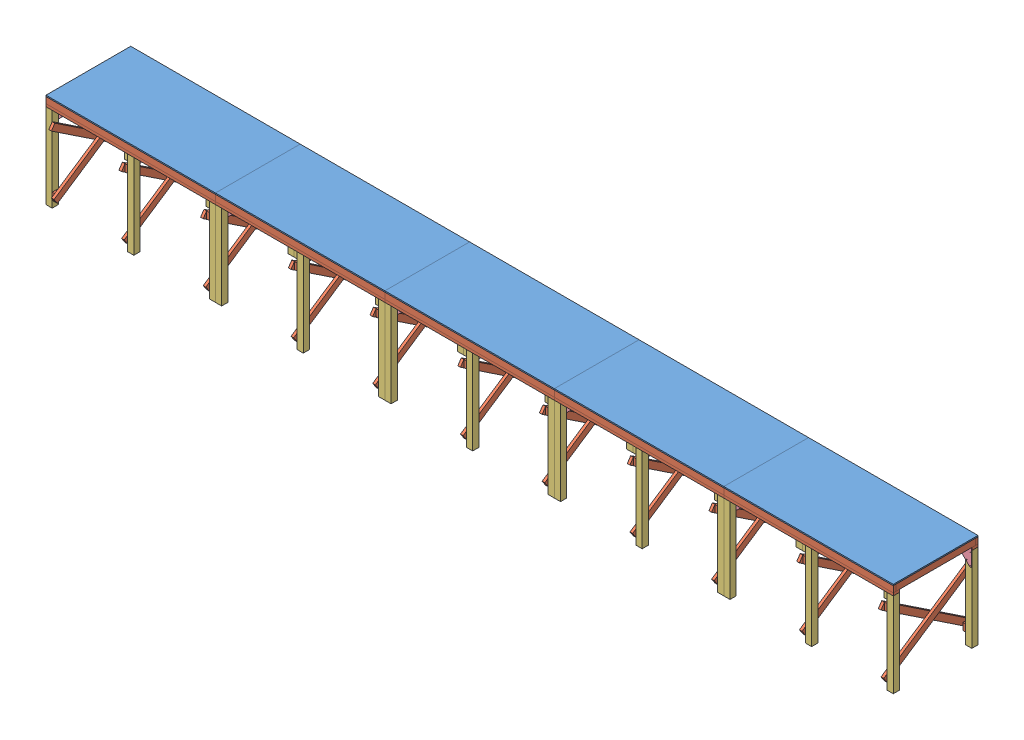
SolidWorks assembly Back Platform, configuration Default. Lengths in mm.
Overall size (12423.68 1373.14 1317.75).
179 component instances, 4 part files, 36 mates.
Components (placement in the parent):
- Platform Top-1: Platform Top [Default] at origin size (2438.4 106.76 1219.2)
  - 4x8-1: 4x8 [Default] at origin size (2438.4 17.86 1219.2)
  - 2x4 Configurable-6: 2x4 Configurable [96" Long] at (0 -53.3781 590.55) x (1 0 0) z (0 0 -1) size (2438.4 88.9 38.1)
  - 2x4 Configurable-7: 2x4 Configurable [96" Long] at (0 -53.3781 -590.55) x (1 0 0) z (0 0 -1) size (2438.4 88.9 38.1)
  - 2x4 Configurable-10: 2x4 Configurable [45" Long] at (-1200.15 -53.3781 0) x (0 0 -1) z (1 0 0) size (1143 88.9 38.1)
  - 2x4 Configurable-11: 2x4 Configurable [45" Long] at (-800.1 -53.3781 0) x (0 0 -1) z (1 0 0) size (1143 88.9 38.1)
  - 2x4 Configurable-12: 2x4 Configurable [45" Long] at (-400.05 -53.3781 0) x (0 0 -1) z (1 0 0) size (1143 88.9 38.1)
  - 2x4 Configurable-13: 2x4 Configurable [45" Long] at (0 -53.3781 0) x (0 0 -1) z (1 0 0) size (1143 88.9 38.1)
  - 2x4 Configurable-14: 2x4 Configurable [45" Long] at (400.05 -53.3781 0) x (0 0 -1) z (1 0 0) size (1143 88.9 38.1)
  - 2x4 Configurable-15: 2x4 Configurable [45" Long] at (800.1 -53.3781 0) x (0 0 -1) z (1 0 0) size (1143 88.9 38.1)
  - 2x4 Configurable-16: 2x4 Configurable [45" Long] at (1200.15 -53.3781 0) x (0 0 -1) z (1 0 0) size (1143 88.9 38.1)
- Stringer Config-1: Stringer Config [1 Wide 4ft High] at (-1510.4642 -1326.0215 -1043.4735) size (2670.08 1373.14 90.54)
  - 4x4 Configurable-1: 4x4 Configurable [48" Length] at (380.1642 -29.1066 522.7735) size (88.9 1219.2 88.9)
  - 2x4 Configurable-1: 2x4 Configurable [96" Long] at (1510.4642 1209.1434 478.3235) x (1 0 0) z (0 -1 0) size (2438.4 88.9 38.1)
  - 4x4 Configurable-2: 4x4 Configurable [48" Length] at (2729.6642 -29.1066 522.7735) size (88.9 1219.2 88.9)
  - Bracket-1: Bracket [Default] at (572.205 1228.1934 524.4153) x (0.707107 0.707107 0) z (0 0 -1) size (343.43 190.77 1.64)
  - Bracket-2: Bracket [Default] at (2448.7234 1228.1934 522.7735) x (-0.707107 0.707107 0) z (0 0 1) size (343.43 190.77 1.64)
  - 4x4 Configurable-4: 4x4 Configurable [48" Length] at (1466.0142 -29.1066 522.7735) x (0 0 1) z (-1 0 0) size (88.9 1219.2 88.9)
  - Bracket-3: Bracket [Default] at (1311.6697 1228.1934 524.4153) x (-1 0 0) z (0 0 -1) size (343.43 190.77 1.64)
- Stringer Config-2: Stringer Config [1 Wide 4ft High] at (1510.4642 -1326.0215 1043.4735) x (-1 0 0) z (0 0 -1) size (2670.08 1373.14 90.54)
  - 4x4 Configurable-1: 4x4 Configurable [48" Length] at (380.1642 -29.1066 522.7735) size (88.9 1219.2 88.9)
  - 2x4 Configurable-1: 2x4 Configurable [96" Long] at (1510.4642 1209.1434 478.3235) x (1 0 0) z (0 -1 0) size (2438.4 88.9 38.1)
  - 4x4 Configurable-2: 4x4 Configurable [48" Length] at (2729.6642 -29.1066 522.7735) size (88.9 1219.2 88.9)
  - Bracket-1: Bracket [Default] at (572.205 1228.1934 524.4153) x (0.707107 0.707107 0) z (0 0 -1) size (343.43 190.77 1.64)
  - Bracket-2: Bracket [Default] at (2448.7234 1228.1934 522.7735) x (-0.707107 0.707107 0) z (0 0 1) size (343.43 190.77 1.64)
  - 4x4 Configurable-4: 4x4 Configurable [48" Length] at (1466.0142 -29.1066 522.7735) x (0 0 1) z (-1 0 0) size (88.9 1219.2 88.9)
  - Bracket-3: Bracket [Default] at (1311.6697 1228.1934 524.4153) x (-1 0 0) z (0 0 -1) size (343.43 190.77 1.64)
- Stringer Config-3: Stringer Config [1 Wide 4ft High] at (927.9358 -1326.0215 -1043.4735) size (2670.08 1373.14 90.54)
  - 4x4 Configurable-1: 4x4 Configurable [48" Length] at (380.1642 -29.1066 522.7735) size (88.9 1219.2 88.9)
  - 2x4 Configurable-1: 2x4 Configurable [96" Long] at (1510.4642 1209.1434 478.3235) x (1 0 0) z (0 -1 0) size (2438.4 88.9 38.1)
  - 4x4 Configurable-2: 4x4 Configurable [48" Length] at (2729.6642 -29.1066 522.7735) size (88.9 1219.2 88.9)
  - Bracket-1: Bracket [Default] at (572.205 1228.1934 524.4153) x (0.707107 0.707107 0) z (0 0 -1) size (343.43 190.77 1.64)
  - Bracket-2: Bracket [Default] at (2448.7234 1228.1934 522.7735) x (-0.707107 0.707107 0) z (0 0 1) size (343.43 190.77 1.64)
  - 4x4 Configurable-4: 4x4 Configurable [48" Length] at (1466.0142 -29.1066 522.7735) x (0 0 1) z (-1 0 0) size (88.9 1219.2 88.9)
  - Bracket-3: Bracket [Default] at (1311.6697 1228.1934 524.4153) x (-1 0 0) z (0 0 -1) size (343.43 190.77 1.64)
- Platform Top-2: Platform Top [Default] at (2438.4 0 0) size (2438.4 106.76 1219.2)
  - 4x8-1: 4x8 [Default] at origin size (2438.4 17.86 1219.2)
  - 2x4 Configurable-6: 2x4 Configurable [96" Long] at (0 -53.3781 590.55) x (1 0 0) z (0 0 -1) size (2438.4 88.9 38.1)
  - 2x4 Configurable-7: 2x4 Configurable [96" Long] at (0 -53.3781 -590.55) x (1 0 0) z (0 0 -1) size (2438.4 88.9 38.1)
  - 2x4 Configurable-10: 2x4 Configurable [45" Long] at (-1200.15 -53.3781 0) x (0 0 -1) z (1 0 0) size (1143 88.9 38.1)
  - 2x4 Configurable-11: 2x4 Configurable [45" Long] at (-800.1 -53.3781 0) x (0 0 -1) z (1 0 0) size (1143 88.9 38.1)
  - 2x4 Configurable-12: 2x4 Configurable [45" Long] at (-400.05 -53.3781 0) x (0 0 -1) z (1 0 0) size (1143 88.9 38.1)
  - 2x4 Configurable-13: 2x4 Configurable [45" Long] at (0 -53.3781 0) x (0 0 -1) z (1 0 0) size (1143 88.9 38.1)
  - 2x4 Configurable-14: 2x4 Configurable [45" Long] at (400.05 -53.3781 0) x (0 0 -1) z (1 0 0) size (1143 88.9 38.1)
  - 2x4 Configurable-15: 2x4 Configurable [45" Long] at (800.1 -53.3781 0) x (0 0 -1) z (1 0 0) size (1143 88.9 38.1)
  - 2x4 Configurable-16: 2x4 Configurable [45" Long] at (1200.15 -53.3781 0) x (0 0 -1) z (1 0 0) size (1143 88.9 38.1)
- Stringer Config-4: Stringer Config [1 Wide 4ft High] at (3948.8642 -1326.0215 1043.4735) x (-1 0 0) z (0 0 -1) size (2670.08 1373.14 90.54)
  - 4x4 Configurable-1: 4x4 Configurable [48" Length] at (380.1642 -29.1066 522.7735) size (88.9 1219.2 88.9)
  - 2x4 Configurable-1: 2x4 Configurable [96" Long] at (1510.4642 1209.1434 478.3235) x (1 0 0) z (0 -1 0) size (2438.4 88.9 38.1)
  - 4x4 Configurable-2: 4x4 Configurable [48" Length] at (2729.6642 -29.1066 522.7735) size (88.9 1219.2 88.9)
  - Bracket-1: Bracket [Default] at (572.205 1228.1934 524.4153) x (0.707107 0.707107 0) z (0 0 -1) size (343.43 190.77 1.64)
  - Bracket-2: Bracket [Default] at (2448.7234 1228.1934 522.7735) x (-0.707107 0.707107 0) z (0 0 1) size (343.43 190.77 1.64)
  - 4x4 Configurable-4: 4x4 Configurable [48" Length] at (1466.0142 -29.1066 522.7735) x (0 0 1) z (-1 0 0) size (88.9 1219.2 88.9)
  - Bracket-3: Bracket [Default] at (1311.6697 1228.1934 524.4153) x (-1 0 0) z (0 0 -1) size (343.43 190.77 1.64)
- Stringer Config-7: Stringer Config [1 Wide 4ft High] at (-927.9358 -1326.0215 1043.4735) x (-1 0 0) z (0 0 -1) size (2670.08 1373.14 90.54)
  - 4x4 Configurable-1: 4x4 Configurable [48" Length] at (380.1642 -29.1066 522.7735) size (88.9 1219.2 88.9)
  - 2x4 Configurable-1: 2x4 Configurable [96" Long] at (1510.4642 1209.1434 478.3235) x (1 0 0) z (0 -1 0) size (2438.4 88.9 38.1)
  - 4x4 Configurable-2: 4x4 Configurable [48" Length] at (2729.6642 -29.1066 522.7735) size (88.9 1219.2 88.9)
  - Bracket-1: Bracket [Default] at (572.205 1228.1934 524.4153) x (0.707107 0.707107 0) z (0 0 -1) size (343.43 190.77 1.64)
  - Bracket-2: Bracket [Default] at (2448.7234 1228.1934 522.7735) x (-0.707107 0.707107 0) z (0 0 1) size (343.43 190.77 1.64)
  - 4x4 Configurable-4: 4x4 Configurable [48" Length] at (1466.0142 -29.1066 522.7735) x (0 0 1) z (-1 0 0) size (88.9 1219.2 88.9)
  - Bracket-3: Bracket [Default] at (1311.6697 1228.1934 524.4153) x (-1 0 0) z (0 0 -1) size (343.43 190.77 1.64)
- Platform Top-4: Platform Top [Default] at (-2438.4 0 0) size (2438.4 106.76 1219.2)
  - 4x8-1: 4x8 [Default] at origin size (2438.4 17.86 1219.2)
  - 2x4 Configurable-6: 2x4 Configurable [96" Long] at (0 -53.3781 590.55) x (1 0 0) z (0 0 -1) size (2438.4 88.9 38.1)
  - 2x4 Configurable-7: 2x4 Configurable [96" Long] at (0 -53.3781 -590.55) x (1 0 0) z (0 0 -1) size (2438.4 88.9 38.1)
  - 2x4 Configurable-10: 2x4 Configurable [45" Long] at (-1200.15 -53.3781 0) x (0 0 -1) z (1 0 0) size (1143 88.9 38.1)
  - 2x4 Configurable-11: 2x4 Configurable [45" Long] at (-800.1 -53.3781 0) x (0 0 -1) z (1 0 0) size (1143 88.9 38.1)
  - 2x4 Configurable-12: 2x4 Configurable [45" Long] at (-400.05 -53.3781 0) x (0 0 -1) z (1 0 0) size (1143 88.9 38.1)
  - 2x4 Configurable-13: 2x4 Configurable [45" Long] at (0 -53.3781 0) x (0 0 -1) z (1 0 0) size (1143 88.9 38.1)
  - 2x4 Configurable-14: 2x4 Configurable [45" Long] at (400.05 -53.3781 0) x (0 0 -1) z (1 0 0) size (1143 88.9 38.1)
  - 2x4 Configurable-15: 2x4 Configurable [45" Long] at (800.1 -53.3781 0) x (0 0 -1) z (1 0 0) size (1143 88.9 38.1)
  - 2x4 Configurable-16: 2x4 Configurable [45" Long] at (1200.15 -53.3781 0) x (0 0 -1) z (1 0 0) size (1143 88.9 38.1)
- Stringer Config-8: Stringer Config [1 Wide 4ft High] at (-3948.8642 -1326.0215 -1043.4735) size (2670.08 1373.14 90.54)
  - 4x4 Configurable-1: 4x4 Configurable [48" Length] at (380.1642 -29.1066 522.7735) size (88.9 1219.2 88.9)
  - 2x4 Configurable-1: 2x4 Configurable [96" Long] at (1510.4642 1209.1434 478.3235) x (1 0 0) z (0 -1 0) size (2438.4 88.9 38.1)
  - 4x4 Configurable-2: 4x4 Configurable [48" Length] at (2729.6642 -29.1066 522.7735) size (88.9 1219.2 88.9)
  - Bracket-1: Bracket [Default] at (572.205 1228.1934 524.4153) x (0.707107 0.707107 0) z (0 0 -1) size (343.43 190.77 1.64)
  - Bracket-2: Bracket [Default] at (2448.7234 1228.1934 522.7735) x (-0.707107 0.707107 0) z (0 0 1) size (343.43 190.77 1.64)
  - 4x4 Configurable-4: 4x4 Configurable [48" Length] at (1466.0142 -29.1066 522.7735) x (0 0 1) z (-1 0 0) size (88.9 1219.2 88.9)
  - Bracket-3: Bracket [Default] at (1311.6697 1228.1934 524.4153) x (-1 0 0) z (0 0 -1) size (343.43 190.77 1.64)
- Platform Top-5: Platform Top [Default] at (-4876.8 0 0) size (2438.4 106.76 1219.2)
  - 4x8-1: 4x8 [Default] at origin size (2438.4 17.86 1219.2)
  - 2x4 Configurable-6: 2x4 Configurable [96" Long] at (0 -53.3781 590.55) x (1 0 0) z (0 0 -1) size (2438.4 88.9 38.1)
  - 2x4 Configurable-7: 2x4 Configurable [96" Long] at (0 -53.3781 -590.55) x (1 0 0) z (0 0 -1) size (2438.4 88.9 38.1)
  - 2x4 Configurable-10: 2x4 Configurable [45" Long] at (-1200.15 -53.3781 0) x (0 0 -1) z (1 0 0) size (1143 88.9 38.1)
  - 2x4 Configurable-11: 2x4 Configurable [45" Long] at (-800.1 -53.3781 0) x (0 0 -1) z (1 0 0) size (1143 88.9 38.1)
  - 2x4 Configurable-12: 2x4 Configurable [45" Long] at (-400.05 -53.3781 0) x (0 0 -1) z (1 0 0) size (1143 88.9 38.1)
  - 2x4 Configurable-13: 2x4 Configurable [45" Long] at (0 -53.3781 0) x (0 0 -1) z (1 0 0) size (1143 88.9 38.1)
  - 2x4 Configurable-14: 2x4 Configurable [45" Long] at (400.05 -53.3781 0) x (0 0 -1) z (1 0 0) size (1143 88.9 38.1)
  - 2x4 Configurable-15: 2x4 Configurable [45" Long] at (800.1 -53.3781 0) x (0 0 -1) z (1 0 0) size (1143 88.9 38.1)
  - 2x4 Configurable-16: 2x4 Configurable [45" Long] at (1200.15 -53.3781 0) x (0 0 -1) z (1 0 0) size (1143 88.9 38.1)
- Stringer Config-9: Stringer Config [1 Wide 4ft High] at (-6387.2642 -1326.0215 -1043.4735) size (2670.08 1373.14 90.54)
  - 4x4 Configurable-1: 4x4 Configurable [48" Length] at (380.1642 -29.1066 522.7735) size (88.9 1219.2 88.9)
  - 2x4 Configurable-1: 2x4 Configurable [96" Long] at (1510.4642 1209.1434 478.3235) x (1 0 0) z (0 -1 0) size (2438.4 88.9 38.1)
  - 4x4 Configurable-2: 4x4 Configurable [48" Length] at (2729.6642 -29.1066 522.7735) size (88.9 1219.2 88.9)
  - Bracket-1: Bracket [Default] at (572.205 1228.1934 524.4153) x (0.707107 0.707107 0) z (0 0 -1) size (343.43 190.77 1.64)
  - Bracket-2: Bracket [Default] at (2448.7234 1228.1934 522.7735) x (-0.707107 0.707107 0) z (0 0 1) size (343.43 190.77 1.64)
  - 4x4 Configurable-4: 4x4 Configurable [48" Length] at (1466.0142 -29.1066 522.7735) x (0 0 1) z (-1 0 0) size (88.9 1219.2 88.9)
  - Bracket-3: Bracket [Default] at (1311.6697 1228.1934 524.4153) x (-1 0 0) z (0 0 -1) size (343.43 190.77 1.64)
- Stringer Config-10: Stringer Config [1 Wide 4ft High] at (-3366.3358 -1326.0215 1043.4735) x (-1 0 0) z (0 0 -1) size (2670.08 1373.14 90.54)
  - 4x4 Configurable-1: 4x4 Configurable [48" Length] at (380.1642 -29.1066 522.7735) size (88.9 1219.2 88.9)
  - 2x4 Configurable-1: 2x4 Configurable [96" Long] at (1510.4642 1209.1434 478.3235) x (1 0 0) z (0 -1 0) size (2438.4 88.9 38.1)
  - 4x4 Configurable-2: 4x4 Configurable [48" Length] at (2729.6642 -29.1066 522.7735) size (88.9 1219.2 88.9)
  - Bracket-1: Bracket [Default] at (572.205 1228.1934 524.4153) x (0.707107 0.707107 0) z (0 0 -1) size (343.43 190.77 1.64)
  - Bracket-2: Bracket [Default] at (2448.7234 1228.1934 522.7735) x (-0.707107 0.707107 0) z (0 0 1) size (343.43 190.77 1.64)
  - 4x4 Configurable-4: 4x4 Configurable [48" Length] at (1466.0142 -29.1066 522.7735) x (0 0 1) z (-1 0 0) size (88.9 1219.2 88.9)
  - Bracket-3: Bracket [Default] at (1311.6697 1228.1934 524.4153) x (-1 0 0) z (0 0 -1) size (343.43 190.77 1.64)
- Stringer Config-11: Stringer Config [1 Wide 4ft High] at (6387.2642 -1326.0215 1043.4735) x (-1 0 0) z (0 0 -1) size (2670.08 1373.14 90.54)
  - 4x4 Configurable-1: 4x4 Configurable [48" Length] at (380.1642 -29.1066 522.7735) size (88.9 1219.2 88.9)
  - 2x4 Configurable-1: 2x4 Configurable [96" Long] at (1510.4642 1209.1434 478.3235) x (1 0 0) z (0 -1 0) size (2438.4 88.9 38.1)
  - 4x4 Configurable-2: 4x4 Configurable [48" Length] at (2729.6642 -29.1066 522.7735) size (88.9 1219.2 88.9)
  - Bracket-1: Bracket [Default] at (572.205 1228.1934 524.4153) x (0.707107 0.707107 0) z (0 0 -1) size (343.43 190.77 1.64)
  - Bracket-2: Bracket [Default] at (2448.7234 1228.1934 522.7735) x (-0.707107 0.707107 0) z (0 0 1) size (343.43 190.77 1.64)
  - 4x4 Configurable-4: 4x4 Configurable [48" Length] at (1466.0142 -29.1066 522.7735) x (0 0 1) z (-1 0 0) size (88.9 1219.2 88.9)
  - Bracket-3: Bracket [Default] at (1311.6697 1228.1934 524.4153) x (-1 0 0) z (0 0 -1) size (343.43 190.77 1.64)
- Platform Top-6: Platform Top [Default] at (4876.8 0 0) size (2438.4 106.76 1219.2)
  - 4x8-1: 4x8 [Default] at origin size (2438.4 17.86 1219.2)
  - 2x4 Configurable-6: 2x4 Configurable [96" Long] at (0 -53.3781 590.55) x (1 0 0) z (0 0 -1) size (2438.4 88.9 38.1)
  - 2x4 Configurable-7: 2x4 Configurable [96" Long] at (0 -53.3781 -590.55) x (1 0 0) z (0 0 -1) size (2438.4 88.9 38.1)
  - 2x4 Configurable-10: 2x4 Configurable [45" Long] at (-1200.15 -53.3781 0) x (0 0 -1) z (1 0 0) size (1143 88.9 38.1)
  - 2x4 Configurable-11: 2x4 Configurable [45" Long] at (-800.1 -53.3781 0) x (0 0 -1) z (1 0 0) size (1143 88.9 38.1)
  - 2x4 Configurable-12: 2x4 Configurable [45" Long] at (-400.05 -53.3781 0) x (0 0 -1) z (1 0 0) size (1143 88.9 38.1)
  - 2x4 Configurable-13: 2x4 Configurable [45" Long] at (0 -53.3781 0) x (0 0 -1) z (1 0 0) size (1143 88.9 38.1)
  - 2x4 Configurable-14: 2x4 Configurable [45" Long] at (400.05 -53.3781 0) x (0 0 -1) z (1 0 0) size (1143 88.9 38.1)
  - 2x4 Configurable-15: 2x4 Configurable [45" Long] at (800.1 -53.3781 0) x (0 0 -1) z (1 0 0) size (1143 88.9 38.1)
  - 2x4 Configurable-16: 2x4 Configurable [45" Long] at (1200.15 -53.3781 0) x (0 0 -1) z (1 0 0) size (1143 88.9 38.1)
- Stringer Config-12: Stringer Config [1 Wide 4ft High] at (3366.3358 -1326.0215 -1043.4735) size (2670.08 1373.14 90.54)
  - 4x4 Configurable-1: 4x4 Configurable [48" Length] at (380.1642 -29.1066 522.7735) size (88.9 1219.2 88.9)
  - 2x4 Configurable-1: 2x4 Configurable [96" Long] at (1510.4642 1209.1434 478.3235) x (1 0 0) z (0 -1 0) size (2438.4 88.9 38.1)
  - 4x4 Configurable-2: 4x4 Configurable [48" Length] at (2729.6642 -29.1066 522.7735) size (88.9 1219.2 88.9)
  - Bracket-1: Bracket [Default] at (572.205 1228.1934 524.4153) x (0.707107 0.707107 0) z (0 0 -1) size (343.43 190.77 1.64)
  - Bracket-2: Bracket [Default] at (2448.7234 1228.1934 522.7735) x (-0.707107 0.707107 0) z (0 0 1) size (343.43 190.77 1.64)
  - 4x4 Configurable-4: 4x4 Configurable [48" Length] at (1466.0142 -29.1066 522.7735) x (0 0 1) z (-1 0 0) size (88.9 1219.2 88.9)
  - Bracket-3: Bracket [Default] at (1311.6697 1228.1934 524.4153) x (-1 0 0) z (0 0 -1) size (343.43 190.77 1.64)
- 2x4 Configurable-1: 2x4 Configurable [60" Long] at (-4978.4 -736.2604 0) x (0 0.554276 0.832333) z (-1 0 0) size (1524 88.9 38.1)
- 2x4 Configurable-2: 2x4 Configurable [60" Long] at (-4940.3 -798.4838 0) x (0 -0.554276 0.832333) z (-1 0 0) size (1524 88.9 38.1)
- 2x4 Configurable-7: 2x4 Configurable [4" Long] at (-4940.3 -327.7047 565.15) x (0 -1 0) z (1 0 0) size (101.6 88.9 38.1)
- 2x4 Configurable-25: 2x4 Configurable [4" Long] at (-4940.3 -1144.8161 -565.15) x (0 -1 0) z (1 0 0) size (101.6 88.9 38.1)
- 2x4 Configurable-26: 2x4 Configurable [4" Long] at (-2501.9 -327.7047 565.15) x (0 -1 0) z (1 0 0) size (101.6 88.9 38.1)
- 2x4 Configurable-27: 2x4 Configurable [4" Long] at (-63.5 -327.7047 565.15) x (0 -1 0) z (1 0 0) size (101.6 88.9 38.1)
- 2x4 Configurable-28: 2x4 Configurable [4" Long] at (2374.9 -327.7047 565.15) x (0 -1 0) z (1 0 0) size (101.6 88.9 38.1)
- 2x4 Configurable-29: 2x4 Configurable [4" Long] at (4813.3 -327.7047 565.15) x (0 -1 0) z (1 0 0) size (101.6 88.9 38.1)
- 2x4 Configurable-30: 2x4 Configurable [60" Long] at (-2501.9 -798.4838 0) x (0 -0.554276 0.832333) z (-1 0 0) size (1524 88.9 38.1)
- 2x4 Configurable-31: 2x4 Configurable [60" Long] at (-63.5 -798.4838 0) x (0 -0.554276 0.832333) z (-1 0 0) size (1524 88.9 38.1)
- 2x4 Configurable-32: 2x4 Configurable [60" Long] at (2374.9 -798.4838 0) x (0 -0.554276 0.832333) z (-1 0 0) size (1524 88.9 38.1)
- 2x4 Configurable-33: 2x4 Configurable [60" Long] at (4813.3 -798.4838 0) x (0 -0.554276 0.832333) z (-1 0 0) size (1524 88.9 38.1)
- 2x4 Configurable-34: 2x4 Configurable [60" Long] at (-2540 -736.2604 0) x (0 0.554276 0.832333) z (-1 0 0) size (1524 88.9 38.1)
- 2x4 Configurable-35: 2x4 Configurable [60" Long] at (-101.6 -736.2604 0) x (0 0.554276 0.832333) z (-1 0 0) size (1524 88.9 38.1)
- 2x4 Configurable-36: 2x4 Configurable [60" Long] at (2336.8 -736.2604 0) x (0 0.554276 0.832333) z (-1 0 0) size (1524 88.9 38.1)
- 2x4 Configurable-37: 2x4 Configurable [60" Long] at (4775.2 -736.2604 0) x (0 0.554276 0.832333) z (-1 0 0) size (1524 88.9 38.1)
- 2x4 Configurable-38: 2x4 Configurable [4" Long] at (-2501.9 -1144.8161 -565.15) x (0 -1 0) z (1 0 0) size (101.6 88.9 38.1)
- 2x4 Configurable-39: 2x4 Configurable [4" Long] at (-63.5 -1144.8161 -565.15) x (0 -1 0) z (1 0 0) size (101.6 88.9 38.1)
- 2x4 Configurable-40: 2x4 Configurable [4" Long] at (2374.9 -1144.8161 -565.15) x (0 -1 0) z (1 0 0) size (101.6 88.9 38.1)
- 2x4 Configurable-41: 2x4 Configurable [4" Long] at (4813.3 -1144.8161 -565.15) x (0 -1 0) z (1 0 0) size (101.6 88.9 38.1)
- 2x4 Configurable-42: 2x4 Configurable [4" Long] at (-3765.55 -327.7047 565.15) x (0 -1 0) z (1 0 0) size (101.6 88.9 38.1)
- 2x4 Configurable-43: 2x4 Configurable [60" Long] at (-3765.55 -798.4838 0) x (0 -0.554276 0.832333) z (-1 0 0) size (1524 88.9 38.1)
- 2x4 Configurable-44: 2x4 Configurable [4" Long] at (-3765.55 -1144.8161 -565.15) x (0 -1 0) z (1 0 0) size (101.6 88.9 38.1)
- 2x4 Configurable-45: 2x4 Configurable [60" Long] at (-3803.65 -736.2604 0) x (0 0.554276 0.832333) z (-1 0 0) size (1524 88.9 38.1)
- 2x4 Configurable-46: 2x4 Configurable [4" Long] at (-1327.15 -327.7047 565.15) x (0 -1 0) z (1 0 0) size (101.6 88.9 38.1)
- 2x4 Configurable-47: 2x4 Configurable [4" Long] at (1111.25 -327.7047 565.15) x (0 -1 0) z (1 0 0) size (101.6 88.9 38.1)
- 2x4 Configurable-48: 2x4 Configurable [4" Long] at (3549.65 -327.7047 565.15) x (0 -1 0) z (1 0 0) size (101.6 88.9 38.1)
- 2x4 Configurable-49: 2x4 Configurable [4" Long] at (5988.05 -327.7047 565.15) x (0 -1 0) z (1 0 0) size (101.6 88.9 38.1)
- 2x4 Configurable-50: 2x4 Configurable [60" Long] at (-1327.15 -798.4838 0) x (0 -0.554276 0.832333) z (-1 0 0) size (1524 88.9 38.1)
- 2x4 Configurable-51: 2x4 Configurable [60" Long] at (1111.25 -798.4838 0) x (0 -0.554276 0.832333) z (-1 0 0) size (1524 88.9 38.1)
- 2x4 Configurable-52: 2x4 Configurable [60" Long] at (3549.65 -798.4838 0) x (0 -0.554276 0.832333) z (-1 0 0) size (1524 88.9 38.1)
- 2x4 Configurable-53: 2x4 Configurable [60" Long] at (5988.05 -798.4838 0) x (0 -0.554276 0.832333) z (-1 0 0) size (1524 88.9 38.1)
- 2x4 Configurable-54: 2x4 Configurable [60" Long] at (-1365.25 -736.2604 0) x (0 0.554276 0.832333) z (-1 0 0) size (1524 88.9 38.1)
- 2x4 Configurable-55: 2x4 Configurable [60" Long] at (1073.15 -736.2604 0) x (0 0.554276 0.832333) z (-1 0 0) size (1524 88.9 38.1)
- 2x4 Configurable-56: 2x4 Configurable [60" Long] at (3511.55 -736.2604 0) x (0 0.554276 0.832333) z (-1 0 0) size (1524 88.9 38.1)
- 2x4 Configurable-57: 2x4 Configurable [60" Long] at (5949.95 -736.2604 0) x (0 0.554276 0.832333) z (-1 0 0) size (1524 88.9 38.1)
- 2x4 Configurable-58: 2x4 Configurable [4" Long] at (-1327.15 -1144.8161 -565.15) x (0 -1 0) z (1 0 0) size (101.6 88.9 38.1)
- 2x4 Configurable-59: 2x4 Configurable [4" Long] at (1111.25 -1144.8161 -565.15) x (0 -1 0) z (1 0 0) size (101.6 88.9 38.1)
- 2x4 Configurable-60: 2x4 Configurable [4" Long] at (3549.65 -1144.8161 -565.15) x (0 -1 0) z (1 0 0) size (101.6 88.9 38.1)
- 2x4 Configurable-61: 2x4 Configurable [4" Long] at (5988.05 -1144.8161 -565.15) x (0 -1 0) z (1 0 0) size (101.6 88.9 38.1)
- 2x4 Configurable-62: 2x4 Configurable [60" Long] at (-5949.95 -798.4838 0) x (0 -0.554276 0.832333) z (-1 0 0) size (1524 88.9 38.1)
- 2x4 Configurable-63: 2x4 Configurable [60" Long] at (-5988.05 -736.2604 0) x (0 0.554276 0.832333) z (-1 0 0) size (1524 88.9 38.1)
- 2x4 Configurable-64: 2x4 Configurable [4" Long] at (-5988.05 -389.9281 -565.15) x (0 -1 0) z (1 0 0) size (101.6 88.9 38.1)
- 2x4 Configurable-65: 2x4 Configurable [4" Long] at (-5988.05 -1207.0395 565.15) x (0 -1 0) z (-1 0 0) size (101.6 88.9 38.1)
Mates (geometry in assembly coordinates):
- Coincident1: coincident anti-aligned: line of Platform Top-1/2x4 Configurable-7 through (1219.2 -97.8281 -609.6) axis (-1 0 0); line of Stringer Config-1/2x4 Configurable-1 through (-1219.2 -97.8281 -609.6) axis (1 0 0)
- Coincident2: coincident anti-aligned: line of Platform Top-1/2x4 Configurable-7 through (1219.2 -97.8281 -571.5) axis (0 0 -1); line of Stringer Config-1/2x4 Configurable-1 through (1219.2 -97.8281 -609.6) axis (0 0 1)
- Coincident3: coincident aligned: line of Platform Top-1/2x4 Configurable-10 through (-1219.2 -97.8281 571.5) axis (0 0 -1); line of Stringer Config-2/2x4 Configurable-1 through (-1219.2 -97.8281 609.6) axis (0 0 -1)
- Coincident4: coincident anti-aligned: line of Platform Top-1/2x4 Configurable-6 through (-1219.2 -97.8281 609.6) axis (0 1 0); line of Stringer Config-2/2x4 Configurable-1 through (-1219.2 -97.8281 609.6) axis (0 -1 0)
- Coincident5: coincident anti-aligned: line of Stringer Config-3/2x4 Configurable-1 through (1219.2 -97.8281 -609.6) axis (1 0 0); line of Platform Top-2/2x4 Configurable-7 through (3657.6 -97.8281 -609.6) axis (-1 0 0)
- Coincident6: coincident anti-aligned: line of Stringer Config-3/2x4 Configurable-1 through (3657.6 -97.8281 -609.6) axis (0 0 1); line of Platform Top-2/2x4 Configurable-16 through (3657.6 -97.8281 571.5) axis (0 0 -1)
- Coincident7: coincident anti-aligned: line of Stringer Config-1/4x4 Configurable-2 through (1219.2 -1355.1281 -520.7) axis (0 0 -1); line of Stringer Config-3/4x4 Configurable-1 through (1219.2 -1355.1281 -609.6) axis (0 0 1)
- Coincident8: coincident aligned: line of Stringer Config-1/4x4 Configurable-2 through (1219.2 -135.9281 -609.6) axis (0 -1 0); line of Stringer Config-3/4x4 Configurable-1 through (1219.2 -135.9281 -609.6) axis (0 -1 0)
- Coincident9: coincident aligned: line of Platform Top-2/2x4 Configurable-6 through (1219.2 -97.8281 609.6) axis (0 0 -1); line of Stringer Config-4/2x4 Configurable-1 through (1219.2 -97.8281 609.6) axis (0 0 -1)
- Coincident10: coincident aligned: line of Platform Top-2/2x4 Configurable-6 through (3657.6 -97.8281 609.6) axis (-1 0 0); line of Stringer Config-4/2x4 Configurable-1 through (3657.6 -97.8281 609.6) axis (-1 0 0)
- Coincident11: coincident anti-aligned: line of Platform Top-4/2x4 Configurable-7 through (-1219.2 -97.8281 -609.6) axis (-1 0 0); line of Stringer Config-8/2x4 Configurable-1 through (-3657.6 -97.8281 -609.6) axis (1 0 0)
- Coincident12: coincident anti-aligned: line of Platform Top-4/2x4 Configurable-16 through (-1219.2 -97.8281 571.5) axis (0 0 -1); line of Stringer Config-8/2x4 Configurable-1 through (-1219.2 -97.8281 -609.6) axis (0 0 1)
- Coincident13: coincident aligned: line of Stringer Config-7/2x4 Configurable-1 through (-3657.6 -97.8281 609.6) axis (0 0 -1); line of Platform Top-4/2x4 Configurable-6 through (-3657.6 -97.8281 609.6) axis (0 0 -1)
- Coincident14: coincident aligned: line of Stringer Config-7/2x4 Configurable-1 through (-1219.2 -97.8281 609.6) axis (-1 0 0); line of Platform Top-4/2x4 Configurable-6 through (-1219.2 -97.8281 609.6) axis (-1 0 0)
- Coincident15: coincident aligned: line of Stringer Config-1/4x4 Configurable-1 through (-1219.2 -135.9281 -609.6) axis (0 -1 0); line of Stringer Config-8/4x4 Configurable-2 through (-1219.2 -135.9281 -609.6) axis (0 -1 0)
- Coincident16: coincident aligned: line of Stringer Config-1/4x4 Configurable-1 through (-1219.2 -1355.1281 -520.7) axis (1 0 0); line of Stringer Config-8/4x4 Configurable-2 through (-1308.1 -1355.1281 -520.7) axis (1 0 0)
- Coincident26: coincident: line of Stringer Config-9/4x4 Configurable-4 through (-4921.25 -135.9281 -609.6) axis (0 -1 0); point of 2x4 Configurable-2
- Coincident27: coincident anti-aligned: plane of Stringer Config-9/4x4 Configurable-4 through (-4921.25 -135.9281 -609.6) normal (-1 0 0); plane of 2x4 Configurable-2 through (-4921.25 -798.4838 0) normal (1 0 0)
- Distance1: distance = 203.2 mm: point of 2x4 Configurable-2; point of Stringer Config-9/4x4 Configurable-4
- Coincident31: coincident: line of Stringer Config-10/4x4 Configurable-4 through (-4921.25 -135.9281 609.6) axis (0 -1 0); point of 2x4 Configurable-2
- Coincident32: coincident anti-aligned: plane of Stringer Config-10/4x4 Configurable-4 through (-4921.25 -135.9281 520.7) normal (-1 0 0); plane of 2x4 Configurable-7 through (-4921.25 -327.7047 565.15) normal (1 0 0)
- Coincident33: coincident aligned: line of Stringer Config-10/4x4 Configurable-4 through (-4921.25 -135.9281 609.6) axis (0 -1 0); line of 2x4 Configurable-7 through (-4921.25 -276.9047 609.6) axis (0 -1 0)
- Distance2: distance = 0 mm: line of 2x4 Configurable-1 through (-4959.35 -276.9047 609.6) axis (-1 0 0); line of Stringer Config-10/4x4 Configurable-4 through (-4921.25 -135.9281 609.6) axis (0 -1 0)
- Coincident40: coincident: point of 2x4 Configurable-1; line of 2x4 Configurable-7 through (-4959.35 -276.9047 520.7) axis (0 0 1)
- Coincident41: coincident anti-aligned: line of Stringer Config-9/4x4 Configurable-4 through (-4921.25 -135.9281 -609.6) axis (0 -1 0); line of 2x4 Configurable-25 through (-4921.25 -1195.6161 -609.6) axis (0 1 0)
- Coincident43: coincident anti-aligned: plane of Stringer Config-9/4x4 Configurable-4 through (-4921.25 -135.9281 -609.6) normal (-1 0 0); plane of 2x4 Configurable-25 through (-4921.25 -1144.8161 -565.15) normal (1 0 0)
- Coincident44: coincident: point of 2x4 Configurable-1; line of 2x4 Configurable-25 through (-4959.35 -1195.6161 -609.6) axis (1 0 0)
- Coincident45: coincident: point of 2x4 Configurable-1; point of 2x4 Configurable-25
- Distance4: distance = 159.512 mm aligned: plane of 2x4 Configurable-25 through (-4959.35 -1195.6161 -609.6) normal (0 -1 0); plane of Stringer Config-9/4x4 Configurable-4 through (-4921.25 -1355.1281 -520.7) normal (0 -1 0)
- Coincident47: coincident anti-aligned: plane of 2x4 Configurable-1 through (-4959.35 -736.2604 0) normal (1 0 0); plane of 2x4 Configurable-25 through (-4959.35 -1144.8161 -565.15) normal (-1 0 0)
- Coincident48: coincident aligned: line of Stringer Config-9/4x4 Configurable-1 through (-6007.1 -135.9281 -520.7) axis (0 -1 0); line of 2x4 Configurable-64 through (-6007.1 -339.1281 -520.7) axis (0 -1 0)
- Coincident49: coincident anti-aligned: plane of Stringer Config-9/4x4 Configurable-1 through (-6007.1 -135.9281 -520.7) normal (1 0 0); plane of 2x4 Configurable-64 through (-6007.1 -389.9281 -565.15) normal (-1 0 0)
- Coincident50: coincident: point of 2x4 Configurable-62; point of 2x4 Configurable-64
- Coincident51: coincident anti-aligned: plane of Stringer Config-10/4x4 Configurable-2 through (-6007.1 -135.9281 609.6) normal (1 0 0); plane of 2x4 Configurable-65 through (-6007.1 -1207.0395 565.15) normal (-1 0 0)
- Coincident52: coincident aligned: line of Stringer Config-10/4x4 Configurable-2 through (-6007.1 -135.9281 520.7) axis (0 -1 0); line of 2x4 Configurable-65 through (-6007.1 -1156.2395 520.7) axis (0 -1 0)
- Coincident53: coincident: point of 2x4 Configurable-62; point of 2x4 Configurable-65
